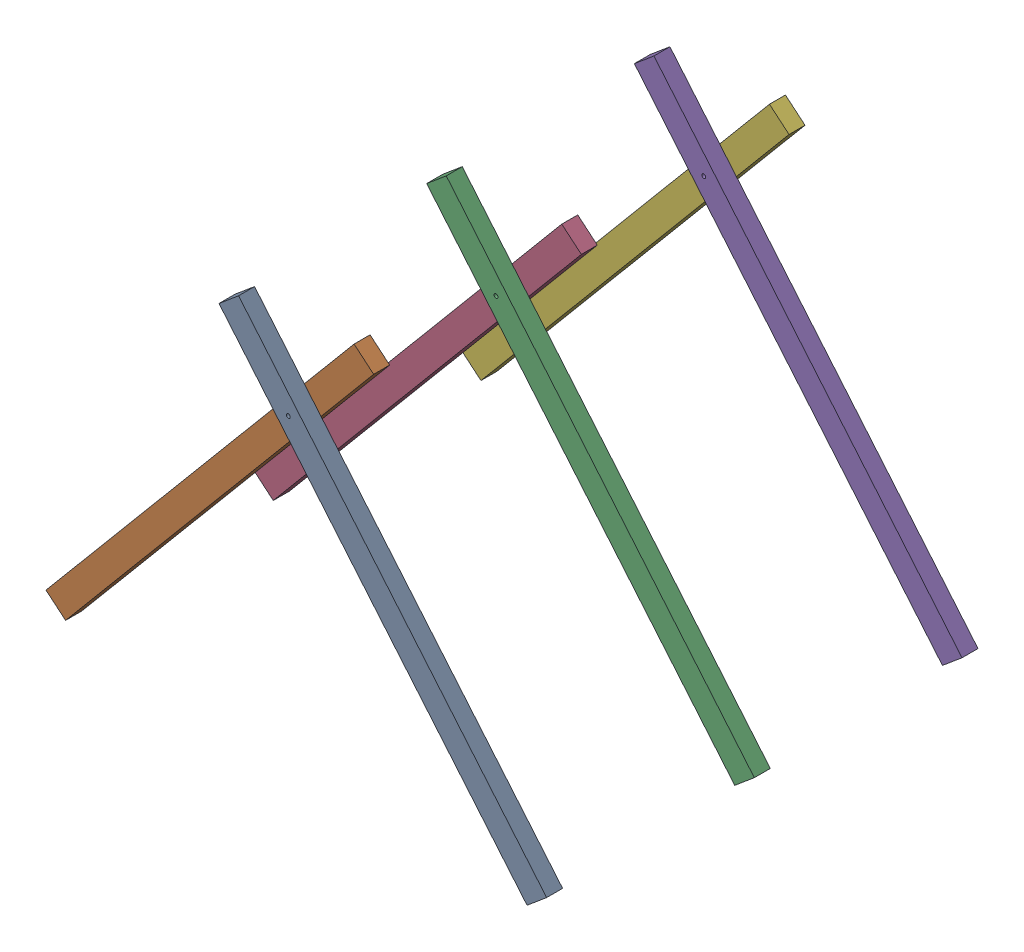
SolidWorks assembly КозлыСБ_БР, configuration По умолчанию. Lengths in mm.
Overall size (1616.83 1200.49 1400).
9 component instances, 1 part files, 4 mates.
Components (placement in the parent):
- КозлыСБ_СКС-1: КозлыСБ_СКС [По умолчанию] at (1494.2625 0 0) x (-1 0 0) z (0 0 -1) size (1616.83 1200.49 100)
  - Брус8050-1: Брус8050 [По умолчанию] at (-61.2836 51.423 0) x (0.642788 0.766044 0) z (-0.766044 0.642788 0) size (1500 50 80)
  - Брус8050-2: Брус8050 [По умолчанию] at (1555.546 51.423 0) x (-0.642788 0.766044 0) z (0.766044 0.642788 0) size (1500 50 80)
- КозлыСБ_СКС-2: КозлыСБ_СКС [По умолчанию] at (1494.2625 0 -650) x (-1 0 0) z (0 0 -1) size (1616.83 1200.49 100)
  - Брус8050-1: Брус8050 [По умолчанию] at (-61.2836 51.423 0) x (0.642788 0.766044 0) z (-0.766044 0.642788 0) size (1500 50 80)
  - Брус8050-2: Брус8050 [По умолчанию] at (1555.546 51.423 0) x (-0.642788 0.766044 0) z (0.766044 0.642788 0) size (1500 50 80)
- КозлыСБ_СКС-3: КозлыСБ_СКС [По умолчанию] at (1494.2625 0 -1300) x (-1 0 0) z (0 0 -1) size (1616.83 1200.49 100)
  - Брус8050-1: Брус8050 [По умолчанию] at (-61.2836 51.423 0) x (0.642788 0.766044 0) z (-0.766044 0.642788 0) size (1500 50 80)
  - Брус8050-2: Брус8050 [По умолчанию] at (1555.546 51.423 0) x (-0.642788 0.766044 0) z (0.766044 0.642788 0) size (1500 50 80)
Mates (geometry in assembly coordinates):
- Совпадение6: coincident: line of КозлыСБ_СКС-1/Брус8050-2 through (0 0 0) axis (0 0 -1)
- Совпадение8: coincident aligned: plane of КозлыСБ_СКС-1/Брус8050-2 through (902.8979 1200.4897 0) normal (0 0 1)
- Совпадение9: coincident: line of КозлыСБ_СКС-1/Брус8050-1 through (1494.2625 0 0) axis (0 0 1)
- Совпадение10: coincident: line of КозлыСБ_СКС-1/Брус8050-2 through (0 0 0) axis (0 0 -1)
